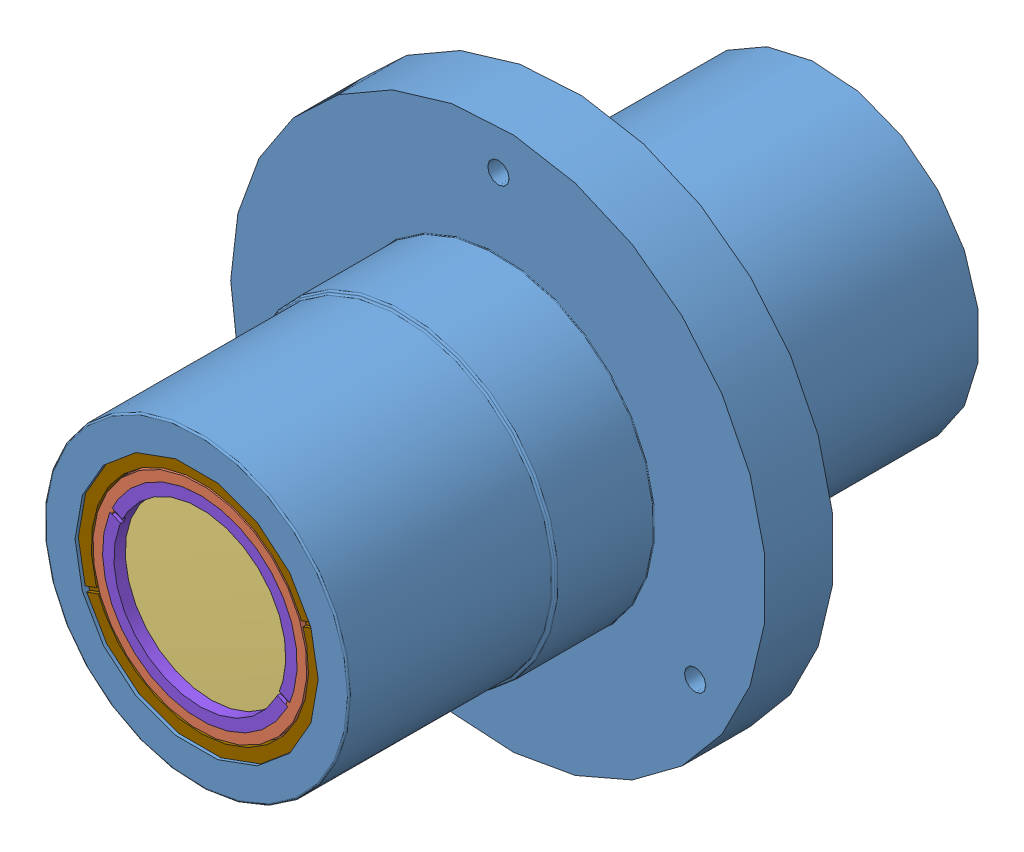
SolidWorks assembly holder_b, configuration Default. Lengths in mm.
Overall size (165 165 197.3).
22 component instances, 22 part files, 38 mates.
Components (placement in the parent):
- holder_b01-1: holder_b01 [ﾃﾞﾌｫﾙﾄ] at (-35.1499 26.4527 -96.9784) size (165 165 193.31)
- holder_b02-1: holder_b02 [Default] at (-35.1499 26.4527 58.5616) x (-0.498782 -0.866727 0) z (0 0 1) size (71 71 40.77)
- G5-1: G5 [Default] at (-35.1499 -478.4199 284.5149) x (0 0 -1) z (1 0 0) size (12 56 56)
- G6-1: G6 [Default] at (-31.6421 -488.9092 412.3134) x (0 0 -1) z (0.999977 0.006806 0) size (14.06 56 56)
- G7-1: G7 [Default] at (-35.1499 -495.2218 537.1324) x (0 0 -1) z (1 0 0) size (16 56 56)
- G8-1: G8 [Default] at (-395.7793 -350.4965 -663.6301) x (0 0 1) z (-0.722576 0.691292 0) size (10 76 76)
- G9-1: G9 [Default] at (-352.6136 -382.199 705.1331) x (0 0 -1) z (0.789705 -0.613487 0) size (14.62 59 59)
- holder_b03-1: holder_b03 [Default] at (-35.1499 26.4527 95.8346) x (-0.410428 -0.911893 0) z (0 0 1) size (60 60 3.5)
- holder_b04-1: holder_b04 [Default] at (-35.1499 26.4527 96.3316) x (-0.339102 0.940749 0) z (0 0 1) size (76 76 3)
- holder_b05-1: holder_b05 [Default] at (-35.1499 26.4527 -96.9654) x (-0.503126 0.864213 0) z (0 0 1) size (78 78 75.48)
- holder_b06-1: holder_b06 [ﾃﾞﾌｫﾙﾄ] at (-35.1499 26.4527 -89.9784) x (-0.882358 0.470579 0) z (0 0 -1) size (82 82.05 3)
- holder_b07-1: holder_b07 [ﾃﾞﾌｫﾙﾄ] at (-35.1499 26.4527 -94.9654) x (0.908144 0.418658 0) z (0 0 -1) size (62 62.05 2)
- holder_b08-1: holder_b08 [Default] at (-35.1499 26.4527 74.3923) size (56 56 1.13)
- holder_b95-1: holder_b95 [Default] at (-35.1499 26.4527 68.5616) size (56 56 0.94)
- holder_b94-1: holder_b94 [Default] at (-35.1499 26.4527 74.0623) size (56 56 0.33)
- holder_b93-1: holder_b93 [Default] at (-35.1499 26.4527 89.5868) size (56 56 2.78)
- holder_b92-1: holder_b92 [Default] at (-35.1499 26.4527 95.2816) x (-0.000879 1 0) z (0 0 1) size (60 60 1.55)
- holder_b96-1: holder_b96 [Default] at (-35.1499 26.4527 -19.2754) size (76 76 0.32)
- holder_b97-2: holder_b97 [Default] at (-35.1499 26.4527 -21.4854) x (0.99592 -0.090238 0) z (0 0 1) size (78 78 0.52)
- holder_b98-1: holder_b98 [Default] at (-35.1499 26.4527 -94.9654) size (62 62 2)
- holder_b99-1: holder_b99 [Default] at (-35.1499 26.4527 -89.9784) size (83 83 3)
- holder_b91-2: holder_b91 [Default] at (-35.1499 26.4527 94.3316) x (0.968934 0.247321 0) z (0 0 1) size (76 76 2)
Mates (geometry in assembly coordinates):
- 同心円1: concentric anti-aligned: cylinder of holder_b02-1; cylinder of holder_b95-1
- 一致1: coincident aligned: circle of holder_b02-1 centre (-35.1499 26.4527 68.5616) axis (0 0 1); circle of holder_b95-1 centre (-35.1499 26.4527 68.5616) axis (0 0 1)
- 同心円2: concentric aligned: cylinder of holder_b02-1; cylinder of G7-1
- 一致2: coincident aligned: circle of G7-1 centre (-35.1499 26.4527 69.5026) axis (0 0 1); circle of holder_b95-1 centre (-35.1499 26.4527 69.5026) axis (0 0 1)
- 一致4: coincident aligned: circle of G7-1 centre (-35.1499 26.4527 74.0623) axis (0 0 1); circle of holder_b94-1 centre (-35.1499 26.4527 74.0623) axis (0 0 1)
- 一致5: coincident aligned: circle of holder_b08-1 centre (-35.1499 26.4527 74.3923) axis (0 0 1); circle of holder_b94-1 centre (-35.1499 26.4527 74.3923) axis (0 0 1)
- 同心円3: concentric aligned: cylinder of holder_b02-1; cylinder of G5-1
- 同心円4: concentric aligned: cylinder of holder_b02-1; cylinder of G6-1
- 一致6: coincident anti-aligned: plane of G6-1 through (-35.3405 54.452 75.5223) normal (0 0 -1); plane of holder_b08-1 through (-35.1499 26.4527 75.5223) normal (0 0 1)
- 同心円5: concentric anti-aligned: cylinder of holder_b02-1; cylinder of holder_b93-1
- 一致7: coincident aligned: circle of G6-1 centre (-35.1499 26.4527 89.5868) axis (0 0 1); circle of holder_b93-1 centre (-35.1499 26.4527 89.5868) axis (0 0 1)
- 一致8: coincident aligned: circle of G5-1 centre (-35.1499 26.4527 92.3638) axis (0 0 1); circle of holder_b93-1 centre (-35.1499 26.4527 92.3638) axis (0 0 1)
- 同心円6: concentric anti-aligned: cylinder of holder_b02-1; cylinder of holder_b92-1
- 同心円7: concentric anti-aligned: cylinder of holder_b02-1; cylinder of holder_b03-1
- 同心円9: concentric aligned: cylinder of holder_b01-1; cylinder of G8-1
- 同心円10: concentric aligned: cylinder of G8-1; cylinder of holder_b96-1
- 一致13: coincident anti-aligned: circle of G8-1 centre (-35.1499 26.4527 -19.2754) axis (0 0 -1); circle of holder_b96-1 centre (-35.1499 26.4527 -19.2754) axis (0 0 1)
- 一致14: coincident anti-aligned: circle of holder_b01-1 centre (-35.1499 26.4527 -18.9584) axis (0 0 -1); circle of holder_b96-1 centre (-35.1499 26.4527 -18.9584) axis (0 0 1)
- 同心円11: concentric aligned: cylinder of holder_b01-1; cylinder of holder_b05-1
- 同心円12: concentric aligned: cylinder of holder_b05-1; cylinder of holder_b97-2
- 一致15: coincident aligned: circle of holder_b05-1 centre (-35.1499 26.4527 -21.4854) axis (0 0 1); circle of holder_b97-2 centre (-35.1499 26.4527 -21.4854) axis (0 0 1)
- 一致27: coincident anti-aligned: circle of holder_b01-1 centre (-35.1499 26.4527 -20.9684) axis (0 0 -1); circle of holder_b97-2 centre (-35.1499 26.4527 -20.9684) axis (0 0 1)
- 同心円13: concentric anti-aligned: cylinder of G9-1; cylinder of holder_b05-1
- 一致17: coincident anti-aligned: plane of G9-1 through (-18.5858 47.7747 -80.3454) normal (0 0 1); plane of holder_b05-1 through (-35.1499 26.4527 -80.3454) normal (0 0 -1)
- 同心円14: concentric anti-aligned: cylinder of holder_b05-1; cylinder of holder_b07-1
- 同心円16: concentric anti-aligned: cylinder of holder_b01-1; cylinder of holder_b06-1
- 一致18: coincident anti-aligned: circle of holder_b98-1 centre (-35.1499 26.4527 -94.9654) axis (0 0 1); circle of holder_b07-1 centre (-35.1499 26.4527 -94.9654) axis (0 0 -1)
- 一致19: coincident anti-aligned: circle of holder_b06-1 centre (-35.1499 26.4527 -89.9784) axis (0 0 -1); circle of holder_b99-1 centre (-35.1499 26.4527 -89.9784) axis (0 0 1)
- 一致24: coincident anti-aligned: plane of holder_b01-1 through (-35.1499 26.4527 58.5616) normal (0 0 1); plane of holder_b02-1 through (-35.1499 26.4527 58.5616) normal (0 0 -1)
- 同心円17: concentric anti-aligned: cylinder of holder_b01-1; cylinder of holder_b02-1
- 同心円18: concentric anti-aligned: cylinder of holder_b01-1; cylinder of holder_b04-1
- 一致29: coincident aligned: circle of holder_b03-1 centre (-35.1499 26.4527 96.8346) axis (0 0 1); circle of holder_b92-1 centre (-35.1499 26.4527 96.8346) axis (0 0 1)
- 同心円19: concentric aligned: cylinder of holder_b04-1; cylinder of holder_b91-2
- 一致31: coincident aligned: circle of holder_b04-1 centre (-35.1499 26.4527 96.3316) axis (0 0 1); circle of holder_b91-2 centre (-35.1499 26.4527 96.3316) axis (0 0 1)
- 一致32: coincident anti-aligned: plane of holder_b01-1 through (-35.1499 26.4527 94.3316) normal (0 0 1); plane of holder_b91-2 through (-35.1499 26.4527 94.3316) normal (0 0 -1)
- 一致34: coincident anti-aligned: plane of holder_b01-1 through (-35.1499 26.4527 -86.9784) normal (0 0 -1); plane of holder_b99-1 through (-35.1499 26.4527 -86.9784) normal (0 0 1)
- 一致35: coincident anti-aligned: plane of holder_b05-1 through (-35.1499 26.4527 -92.9654) normal (0 0 -1); plane of holder_b98-1 through (-35.1499 26.4527 -92.9654) normal (0 0 1)
- 一致37: coincident anti-aligned: plane of holder_b02-1 through (-35.1499 26.4527 95.2816) normal (0 0 1); plane of holder_b92-1 through (-35.1499 26.4527 95.2816) normal (0 0 -1)
